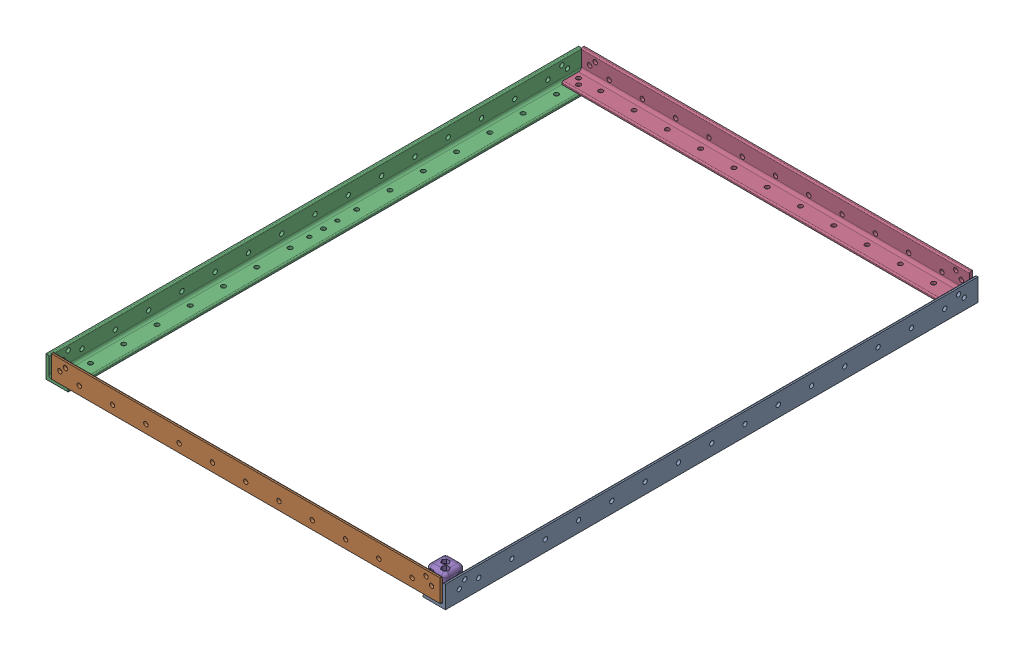
SolidWorks assembly Horizontal Assembly, configuration Default. Lengths in mm.
Overall size (457.2 28.57 609.6).
5 component instances, 3 part files, 13 mates.
Components (placement in the parent):
- Long-Side Horizontal L-Bar-1: Long-Side Horizontal L-Bar [8982K402] at origin size (25.4 25.4 609.6)
- Short-Side Horizontal L-Bar-1: Short-Side Horizontal L-Bar [8982K402] at (-298.45 3.175 292.1) x (0 0 1) z (-1 0 0) size (25.4 25.4 444.5)
- Long-Side Horizontal L-Bar-2: Long-Side Horizontal L-Bar [8982K402] at (-431.8 0 0) x (-1 0 0) z (0 0 -1) size (25.4 25.4 609.6)
- Short-Side Horizontal L-Bar-2: Short-Side Horizontal L-Bar [8982K402] at (-133.35 3.175 -292.1) x (0 0 -1) z (1 0 0) size (25.4 25.4 444.5)
- Nut Holder-1: Nut Holder [Default] at (-4.7625 15.875 287.3375) x (-1 0 0) z (0 -1 0) size (22.23 22.23 22.23)
Mates (geometry in assembly coordinates):
- Coincident1: coincident anti-aligned: plane of Long-Side Horizontal L-Bar-1 through (6.35 -9.525 304.8) normal (0 1 0); plane of Short-Side Horizontal L-Bar-1 through (-603.25 -9.525 279.4) normal (0 -1 0)
- Parallel1: parallel aligned: plane of Long-Side Horizontal L-Bar-1 through (12.7 -12.7 304.8) normal (1 0 0); plane of Short-Side Horizontal L-Bar-1 through (6.35 14.2875 303.2125) normal (1 0 0)
- Coincident4: coincident aligned: plane of Long-Side Horizontal L-Bar-1 through (11.1125 11.1125 304.8) normal (0 0 1); plane of Short-Side Horizontal L-Bar-1 through (-603.25 -9.525 304.8) normal (0 0 1)
- Coincident5: coincident anti-aligned: circle of Long-Side Horizontal L-Bar-1; circle of Short-Side Horizontal L-Bar-1
- Coincident6: coincident anti-aligned: cylinder of Short-Side Horizontal L-Bar-1; cylinder of Long-Side Horizontal L-Bar-2 through (-431.8 -254 292.1) axis (0 1 0) radius 2.5
- Coincident7: coincident aligned: plane of Short-Side Horizontal L-Bar-1 through (-603.25 -9.525 304.8) normal (0 0 1); plane of Long-Side Horizontal L-Bar-2 through (-442.9125 11.1125 304.8) normal (0 0 1)
- Coincident8: coincident anti-aligned: plane of Short-Side Horizontal L-Bar-1 through (-603.25 -9.525 279.4) normal (0 -1 0); plane of Long-Side Horizontal L-Bar-2 through (-438.15 -9.525 -304.8) normal (0 1 0)
- Coincident10: coincident anti-aligned: plane of Long-Side Horizontal L-Bar-2 through (-438.15 -9.525 -304.8) normal (0 1 0); plane of Short-Side Horizontal L-Bar-2 through (171.45 -9.525 -279.4) normal (0 -1 0)
- Concentric1: concentric aligned: cylinder of Long-Side Horizontal L-Bar-2 through (-425.45 -254 -285.75) axis (0 1 0) radius 2.5; cylinder of Short-Side Horizontal L-Bar-2 through (-425.45 -250.825 -285.75) axis (0 1 0) radius 2.5
- Concentric2: concentric aligned: cylinder of Long-Side Horizontal L-Bar-2 through (-431.8 -254 -292.1) axis (0 1 0) radius 2.5; cylinder of Short-Side Horizontal L-Bar-2 through (-431.8 -250.825 -292.1) axis (0 1 0) radius 2.5
- Coincident11: coincident anti-aligned: plane of Short-Side Horizontal L-Bar-1 through (-603.25 -6.35 298.45) normal (0 1 0); plane of Nut Holder-1 through (-4.7625 -6.35 287.3375) normal (0 -1 0)
- Concentric3: concentric aligned: cylinder of Short-Side Horizontal L-Bar-1 through (-6.35 -250.825 285.75) axis (0 1 0) radius 2.5; cylinder of Nut Holder-1 through (-6.35 -9.525 285.75) axis (0 1 0) radius 2.25
- Concentric4: concentric aligned: cylinder of Short-Side Horizontal L-Bar-1 through (0 -250.825 292.1) axis (0 1 0) radius 2.5; cylinder of Nut Holder-1 through (0 -9.525 292.1) axis (0 1 0) radius 2.25
